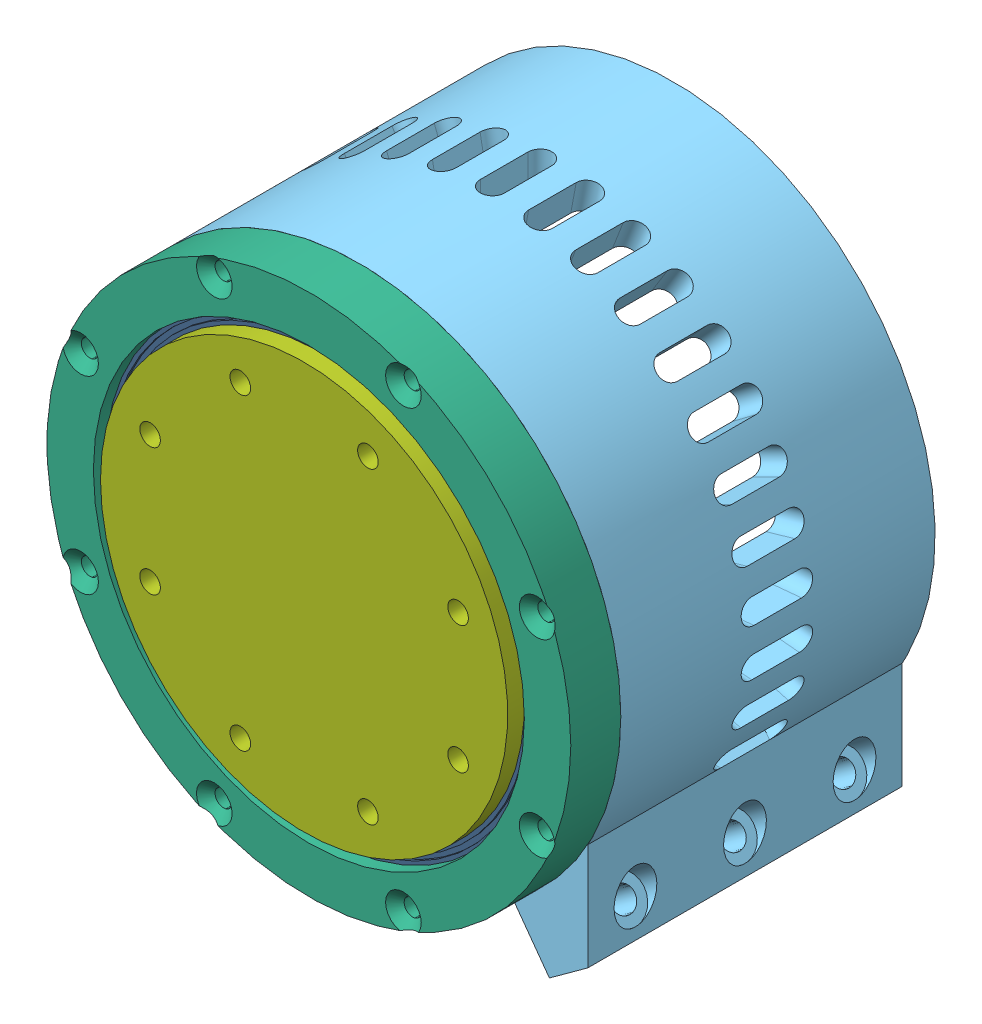
SolidWorks assembly OpenTorque, configuration Default. Lengths in mm.
Overall size (110 110.02 77.5).
21 component instances, 13 part files, 0 mates.
Components (placement in the parent):
- OpenTorque.STEP-1: OpenTorque.STEP [Default] at origin size (110 110.02 95)
  - V2 Gears v31.STEP-1: V2 Gears v31.STEP [Default] at (0 0 40) size (68.62 59.43 32)
    - Sun Gear.STEP-1: Sun Gear.STEP [Default] at origin size (40 40 25.05)
    - Planet Gear.STEP-1: Planet Gear.STEP [Default] at (0 27 1) size (43.38 43.03 18.08)
    - Planet Gear.STEP-2: Planet Gear.STEP [Default] at (-23.3827 -13.5 1) x (-0.5 0.866025 0) z (0 0 1) size (43.38 43.03 18.08)
    - Planet Gear.STEP-3: Planet Gear.STEP [Default] at (23.3827 -13.5 1) x (-0.5 -0.866025 0) z (0 0 1) size (43.38 43.03 18.08)
    - F625ZZ.STEP-1: F625ZZ.STEP [Default] at (0 27 10) size (16 16 5)
    - M5x30 Dowel Pin.STEP-1: M5x30 Dowel Pin.STEP [Default] at origin size (5 5 30)
    - F625ZZ.STEP-2: F625ZZ.STEP [Default] at (-23.3827 -13.5 10) x (-0.5 0.866025 0) z (0 0 1) size (16 16 5)
    - F625ZZ.STEP-3: F625ZZ.STEP [Default] at (23.3827 -13.5 10) x (-0.5 -0.866025 0) z (0 0 1) size (16 16 5)
    - M5x30 Dowel Pin.STEP-2: M5x30 Dowel Pin.STEP [Default] x (-0.5 0.866025 0) z (0 0 1) size (5 5 30)
    - M5x30 Dowel Pin.STEP-3: M5x30 Dowel Pin.STEP [Default] x (-0.5 -0.866025 0) z (0 0 1) size (5 5 30)
  - Actuator Housing.STEP-1: Actuator Housing.STEP [Default] at origin size (110 110.02 66)
  - Bearing Retainer.STEP-1: Bearing Retainer.STEP [Default] at origin size (110 110 10.54)
  - Planet Carrier A.STEP-1: Planet Carrier A.STEP [Default] at origin size (85.5 85.5 11.5)
  - Planet Carrier C.STEP-1: Planet Carrier C.STEP [Default] at origin size (89.5 89.5 11.5)
  - Planet Carrier B.STEP-1: Planet Carrier B.STEP [Default] at origin size (85.5 85.5 22.5)
  - Backplate.STEP-1: Backplate.STEP [Default] at origin size (110 110 7.56) (hidden)
  - Encoder Cover.STEP-1: Encoder Cover.STEP [Default] at origin size (50 47.2 10) (hidden)
  - Encoder Magnet Holder.STEP-1: Encoder Magnet Holder.STEP [Default] at origin size (25 25 5) (hidden)
  - RA-8008C Cross Roller Bearing.STEP-1: RA-8008C Cross Roller Bearing.STEP [Default] at origin size (96 96 8)
